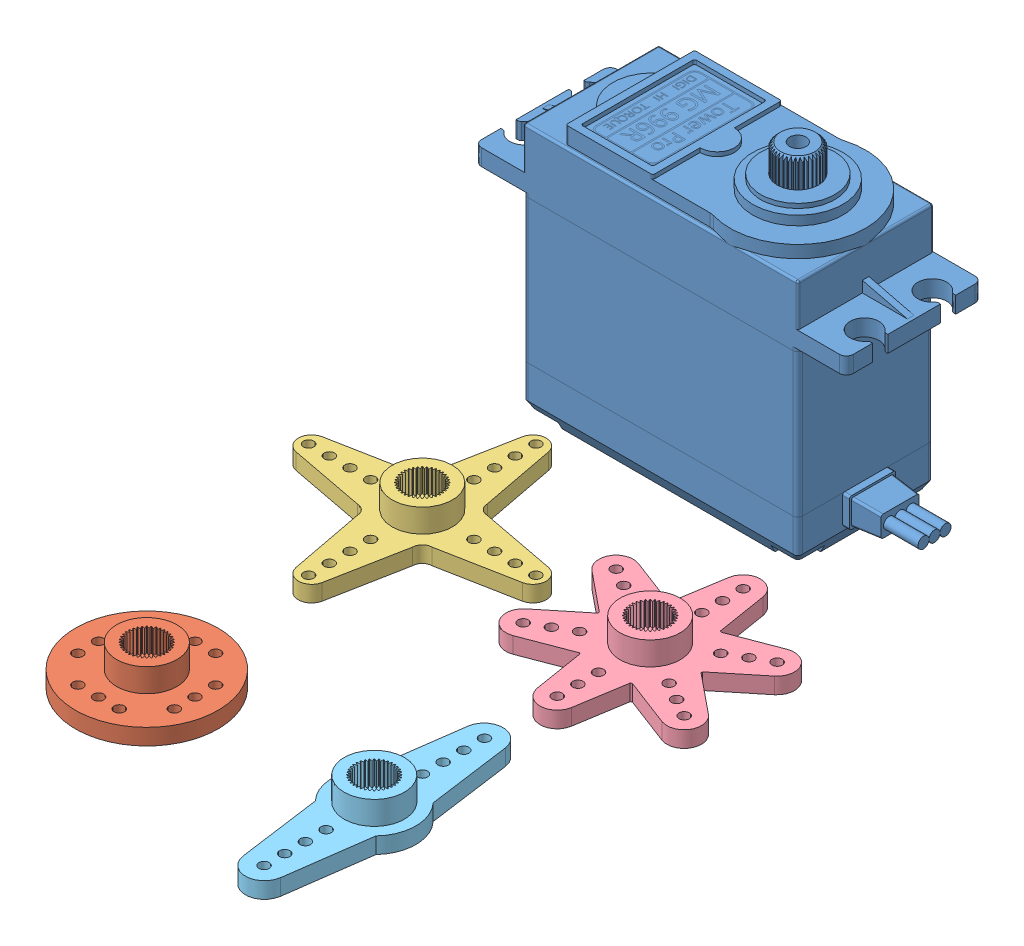
SolidWorks assembly Servo Motor MG996R  With Attachments, configuration Default. Lengths in mm.
Overall size (65.45 44.55 100.11).
5 component instances, 5 part files, 0 mates.
Components (placement in the parent):
- servoMotorMG996R-1: servoMotorMG996R [Default] at origin size (56.95 44.55 19.7)
- attachmentCircular-1: attachmentCircular [Default] at (-13.0508 -28.3 71.3863) size (20.7 5.75 20.7)
- attachmentCross-1: attachmentCross [Default] at (-13.1134 -28.3 31.319) size (36 5.75 36)
- attachmentStar-1: attachmentStar [Default] at (20.141 -28.3 31.4797) size (28.38 5.75 32)
- attachmentStraight-1: attachmentStraight [Default] at (20.1564 -28.3 71.5599) size (12.1 5.75 37.4)
